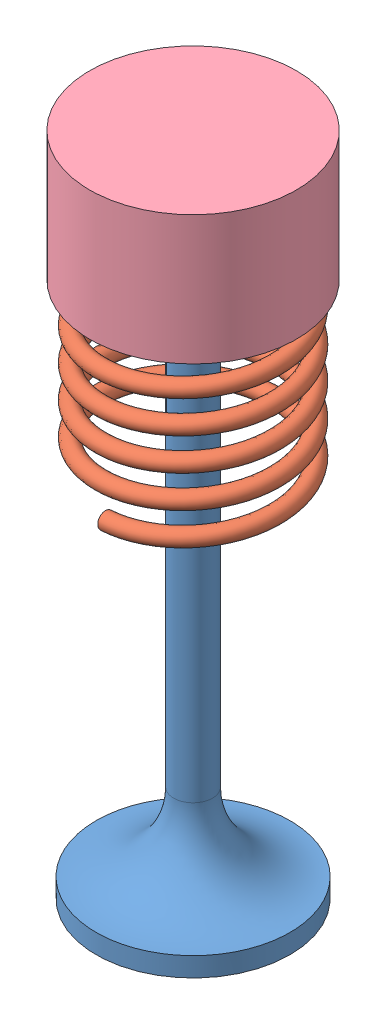
SolidWorks assembly engine_valve_system, configuration Default. Lengths in mm.
Overall size (32.04 103 32.04).
5 component instances, 4 part files, 8 mates.
Components (placement in the parent):
- engine_valve-1: engine_valve [Default] at (13.4043 -34.4776 46.0779) size (30 100 30)
- valve_spring-1: valve_spring [Default] at (13.4043 -19.0822 46.0779) size (32.04 39.25 32.04)
- engine_valve_lock-1: engine_valve_lock [Default] at (13.4043 -19.0822 46.0779) size (10 6 5)
- engine_valve_lock-2: engine_valve_lock [Default] at (13.4043 -19.0822 46.0779) x (-1 0 0) z (0 0 -1) size (10 6 5)
- bucket_tappet-1: bucket_tappet [Default] at (13.4043 -28.5822 46.0779) size (32 20 32)
Mates (geometry in assembly coordinates):
- Concentric1: concentric anti-aligned: cylinder of engine_valve-1 through (13.4043 69.1716 46.0779) axis (0 1 0) radius 2; cylinder of engine_valve_lock-1 through (13.4043 -19.0822 46.0779) axis (0 -1 0) radius 2
- Coincident1: coincident anti-aligned: plane of engine_valve-1 through (13.4043 -19.5822 46.0779) normal (0 1 0); plane of engine_valve_lock-1 through (13.4043 -19.5822 46.0779) normal (0 -1 0)
- Concentric6: concentric anti-aligned: cylinder of engine_valve-1 through (13.4043 69.1716 46.0779) axis (0 1 0) radius 2; cylinder of engine_valve_lock-2 through (13.4043 -19.0822 46.0779) axis (0 -1 0) radius 2
- Coincident3: coincident: point of engine_valve_lock-1; point of engine_valve_lock-2
- Concentric7: concentric anti-aligned: cylinder of valve_spring-1 through (13.4043 -25.0822 46.0779) axis (0 1 0) radius 5; cylinder of engine_valve_lock-2 through (13.4043 -19.0822 46.0779) axis (0 -1 0) radius 5
- Coincident4: coincident anti-aligned: circle of valve_spring-1; circle of engine_valve_lock-1
- Coincident5: coincident anti-aligned: plane of engine_valve-1 through (13.4043 -11.5822 46.0779) normal (0 1 0); plane of bucket_tappet-1 through (13.4043 -11.5822 46.0779) normal (0 -1 0)
- Concentric8: concentric anti-aligned: cylinder of valve_spring-1 through (13.4043 -16.0822 46.0779) axis (0 -1 0) radius 15; cylinder of bucket_tappet-1 through (13.4043 -28.5822 46.0779) axis (0 1 0) radius 15
